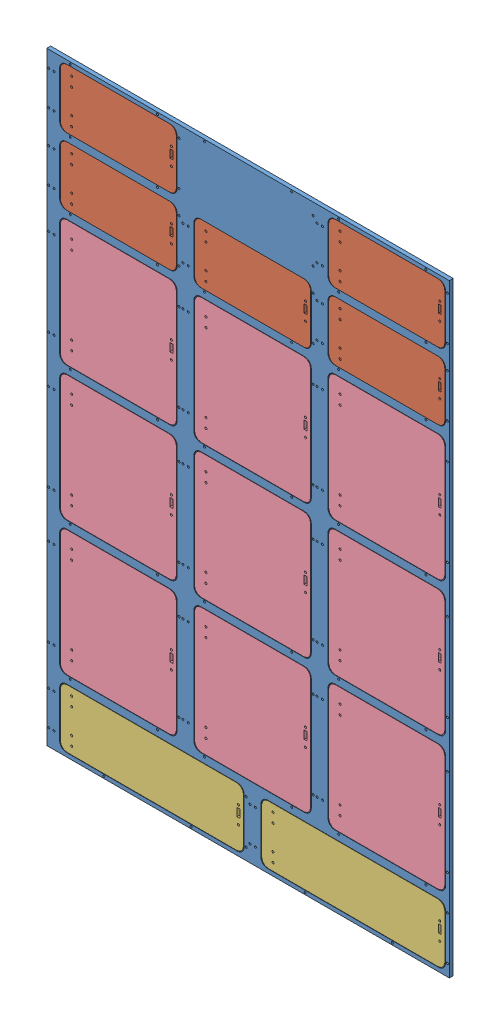
SolidWorks assembly Front+doors, configuration Default. Lengths in mm.
Overall size (600 900 5.8).
17 component instances, 4 part files, 3 mates.
Components (placement in the parent):
- LargeFront-1: LargeFront [Default] at origin size (600 900 5.8)
- door(100x200)-1: door(100x200) [Default] at (20.2 750 0) size (173 88.4 5.8)
- door(100x300)-1: door(100x300) [Default] at (20.2 50 0) size (273 87.4 5.8)
- door(200x200)-1: door(200x200) [Default] at (106.7 200 0) size (173 187.4 5.8)
- door(100x200)-2: door(100x200) [Default] at (20.2 850 0) size (173 88.4 5.8)
- door(100x200)-3: door(100x200) [Default] at (220.2 750 0) size (173 88.4 5.8)
- door(100x200)-4: door(100x200) [Default] at (420.2 750 0) size (173 88.4 5.8)
- door(100x200)-5: door(100x200) [Default] at (420.2 850 0) size (173 88.4 5.8)
- door(200x200)-2: door(200x200) [Default] at (106.7 400 0) size (173 187.4 5.8)
- door(200x200)-3: door(200x200) [Default] at (106.7 600 0) size (173 187.4 5.8)
- door(200x200)-4: door(200x200) [Default] at (306.7 200 0) size (173 187.4 5.8)
- door(200x200)-5: door(200x200) [Default] at (306.7 400 0) size (173 187.4 5.8)
- door(200x200)-6: door(200x200) [Default] at (306.7 600 0) size (173 187.4 5.8)
- door(200x200)-7: door(200x200) [Default] at (506.7 200 0) size (173 187.4 5.8)
- door(200x200)-8: door(200x200) [Default] at (506.7 400 0) size (173 187.4 5.8)
- door(200x200)-9: door(200x200) [Default] at (506.7 600 0) size (173 187.4 5.8)
- door(100x300)-2: door(100x300) [Default] at (320.2 50 0) size (273 87.4 5.8)
Mates (geometry in assembly coordinates):
- ProfileCenter1: profile center aligned: line of door(200x200)-1 through (183.2 293.7 5.8) axis (-1 0 0); line of LargeFront-1 through (184.2 294.2 5.8) axis (-1 0 0)
- ProfileCenter2: profile center aligned: line of door(100x300)-1 through (253 30.2 6.3) axis (0 1 0); line of LargeFront-1 through (255 284.2 94.2) axis (0 -1 0)
- ProfileCenter3: profile center aligned: line of door(100x200)-1 through (30.2 705.8 5.8) axis (1 0 0); line of LargeFront-1 through (29.2 705.8 5.8) axis (1 0 0)
